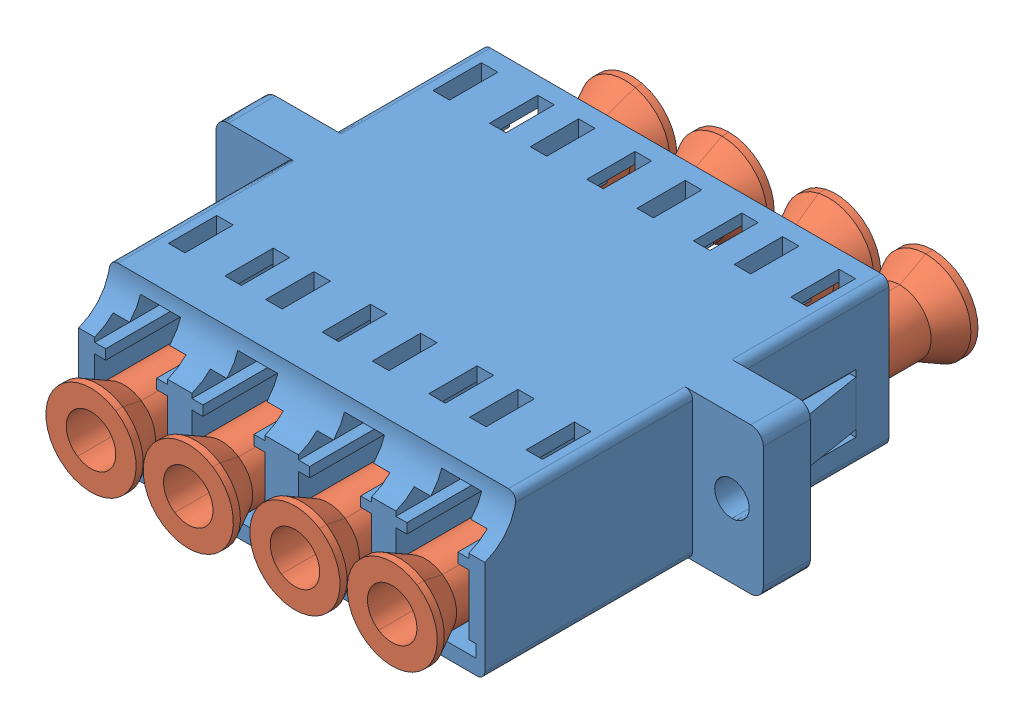
SolidWorks assembly Baugruppe4, configuration Standard. Lengths in mm.
Overall size (34.9 10.05 34.47).
9 component instances, 2 part files, 21 mates.
Components (placement in the parent):
- LC Adaptor-1: LC Adaptor [Standard] at (-28.4856 -9.35 -16.25) x (1 0 0) z (0 -1 0) size (34.9 25.75 9.35)
- LC Adaptor Dust Cap-1: LC Adaptor Dust Cap [Standard] at (-27.05 -6.075 2.56) x (-0.837169 0.546944 0) z (-0.546944 -0.837169 0) size (5.75 16.66 5.75)
- LC Adaptor Dust Cap-2: LC Adaptor Dust Cap [Standard] at (-20.85 -6.075 2.56) x (-0.837169 0.546944 0) z (-0.546944 -0.837169 0) size (5.75 16.66 5.75)
- LC Adaptor Dust Cap-3: LC Adaptor Dust Cap [Standard] at (-14.05 -6.075 2.56) x (-0.837169 0.546944 0) z (-0.546944 -0.837169 0) size (5.75 16.66 5.75)
- LC Adaptor Dust Cap-4: LC Adaptor Dust Cap [Standard] at (-7.85 -6.075 2.56) x (-0.837169 0.546944 0) z (-0.546944 -0.837169 0) size (5.75 16.66 5.75)
- LC Adaptor Dust Cap-5: LC Adaptor Dust Cap [Standard] at (-27.05 -6.075 -31.91) x (0.972668 -0.232198 0) z (-0.232198 -0.972668 0) size (5.75 16.66 5.75)
- LC Adaptor Dust Cap-6: LC Adaptor Dust Cap [Standard] at (-20.85 -6.075 -31.91) x (1 0 0) z (0 -1 0) size (5.75 16.66 5.75)
- LC Adaptor Dust Cap-7: LC Adaptor Dust Cap [Standard] at (-14.05 -6.075 -31.91) x (0.97427 0.225385 0) z (0.225385 -0.97427 0) size (5.75 16.66 5.75)
- LC Adaptor Dust Cap-8: LC Adaptor Dust Cap [Standard] at (-7.85 -6.075 -31.91) x (1 0 0) z (0 -1 0) size (5.75 16.66 5.75)
Mates (geometry in assembly coordinates):
- Deckungsgleich1: coincident anti-aligned: plane of LC Adaptor-1 through (6.4144 -9.35 -14.1) normal (0 0 1); plane of LC Adaptor Dust Cap-4 through (27.05 -6.075 -14.1) normal (0 0 -1)
- Deckungsgleich2: coincident anti-aligned: plane of LC Adaptor-1 through (6.4144 -9.35 -14.1) normal (0 0 1); plane of LC Adaptor Dust Cap-3 through (20.85 -6.075 -14.1) normal (0 0 -1)
- Deckungsgleich3: coincident anti-aligned: plane of LC Adaptor-1 through (6.4144 -9.35 -14.1) normal (0 0 1); plane of LC Adaptor Dust Cap-2 through (14.05 -6.075 -14.1) normal (0 0 -1)
- Deckungsgleich4: coincident anti-aligned: plane of LC Adaptor-1 through (6.4144 -9.35 -14.1) normal (0 0 1); plane of LC Adaptor Dust Cap-1 through (7.85 -6.075 -14.1) normal (0 0 -1)
- Konzentrisch1: concentric anti-aligned: cylinder of LC Adaptor-1 through (27.05 -6.075 -10.6) axis (0 0 -1) radius 1; cylinder of LC Adaptor Dust Cap-4 through (27.05 -6.075 -5.64) axis (0 0 1) radius 1.575
- Konzentrisch2: concentric anti-aligned: cylinder of LC Adaptor-1 through (20.85 -6.075 -10.6) axis (0 0 -1) radius 1; cylinder of LC Adaptor Dust Cap-3 through (20.85 -6.075 -5.64) axis (0 0 1) radius 1.575
- Konzentrisch3: concentric anti-aligned: cylinder of LC Adaptor-1 through (14.05 -6.075 -10.6) axis (0 0 -1) radius 1; cylinder of LC Adaptor Dust Cap-2 through (14.05 -6.075 -5.64) axis (0 0 1) radius 1.575
- Konzentrisch4: concentric anti-aligned: cylinder of LC Adaptor-1 through (7.85 -6.075 -10.6) axis (0 0 -1) radius 1; cylinder of LC Adaptor Dust Cap-1 through (7.85 -6.075 -5.64) axis (0 0 1) radius 1.575
- Deckungsgleich5: coincident anti-aligned: plane of LC Adaptor-1 through (6.4144 -9.35 -15.25) normal (0 0 -1); plane of LC Adaptor Dust Cap-5 through (7.85 -6.075 -15.25) normal (0 0 1)
- Deckungsgleich6: coincident anti-aligned: plane of LC Adaptor-1 through (6.4144 -9.35 -15.25) normal (0 0 -1); plane of LC Adaptor Dust Cap-5 through (7.85 -6.075 -15.25) normal (0 0 1)
- Deckungsgleich7: coincident anti-aligned: plane of LC Adaptor-1 through (6.4144 -9.35 -15.25) normal (0 0 -1); plane of LC Adaptor Dust Cap-6 through (14.05 -6.075 -15.25) normal (0 0 1)
- Deckungsgleich8: coincident anti-aligned: plane of LC Adaptor-1 through (6.4144 -9.35 -15.25) normal (0 0 -1); plane of LC Adaptor Dust Cap-8 through (27.05 -6.075 -15.25) normal (0 0 1)
- Konzentrisch5: concentric aligned: cylinder of LC Adaptor-1 through (7.85 -6.075 -10.6) axis (0 0 -1) radius 1; cylinder of LC Adaptor Dust Cap-5 through (7.85 -6.075 -23.71) axis (0 0 -1) radius 1.575
- Konzentrisch6: concentric aligned: cylinder of LC Adaptor-1 through (14.05 -6.075 -10.6) axis (0 0 -1) radius 1; cylinder of LC Adaptor Dust Cap-6 through (14.05 -6.075 -23.71) axis (0 0 -1) radius 1.575
- Konzentrisch7: concentric aligned: cylinder of LC Adaptor-1 through (20.85 -6.075 -10.6) axis (0 0 -1) radius 1; cylinder of LC Adaptor Dust Cap-7 through (20.85 -6.075 -23.71) axis (0 0 -1) radius 1.575
- Konzentrisch8: concentric aligned: cylinder of LC Adaptor-1 through (27.05 -6.075 -10.6) axis (0 0 -1) radius 1; cylinder of LC Adaptor Dust Cap-8 through (27.05 -6.075 -23.71) axis (0 0 -1) radius 1.575
- Deckungsgleich11: coincident anti-aligned: plane of LC Adaptor-1 through (6.4144 -9.35 -15.25) normal (0 0 -1); plane of LC Adaptor Dust Cap-7 through (20.85 -6.075 -15.25) normal (0 0 1)
- Parallel3: parallel: plane of LC Adaptor-1 through (4.5 0 -25.75) normal (-1 0 0); line of LC Adaptor Dust Cap-5 through (7.4843 -7.607 -31.91) axis (0 0 1)
- Deckungsgleich14: coincident aligned: plane of ? through (4.5 0 0) normal (0 0 1)
- Deckungsgleich18: coincident aligned: plane of LC Adaptor-1 through (-28.4856 0 -16.25) normal (0 1 0); plane of assembly
- Deckungsgleich19: coincident aligned: plane of LC Adaptor-1 through (0 0 -13.25) normal (1 0 0); plane of assembly
